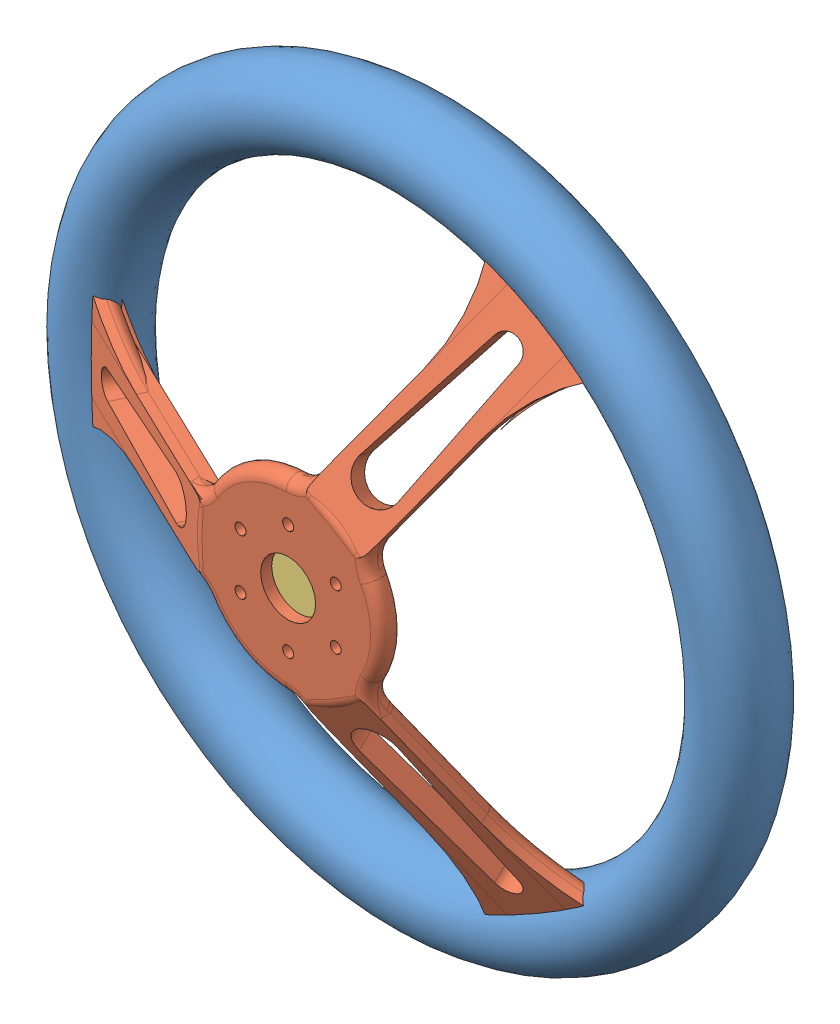
SolidWorks assembly ensamblaje volante, configuration Default. Lengths in mm.
Overall size (325 325 81.24).
3 component instances, 3 part files, 0 mates.
Components (placement in the parent):
- exterior volante 1-1: exterior volante 1 [Default] at (69.436 -2.5195 -103.3423) size (325 325 35)
- volante2-1: volante2 [Default] at (69.436 -2.5195 -53.3423) size (250.43 286.06 66.85)
- tapa volante-1: tapa volante [Default] at (69.436 -2.5195 -53.3423) x (0.228885 0.973453 0) z (0 0 1) size (40 40 5)
